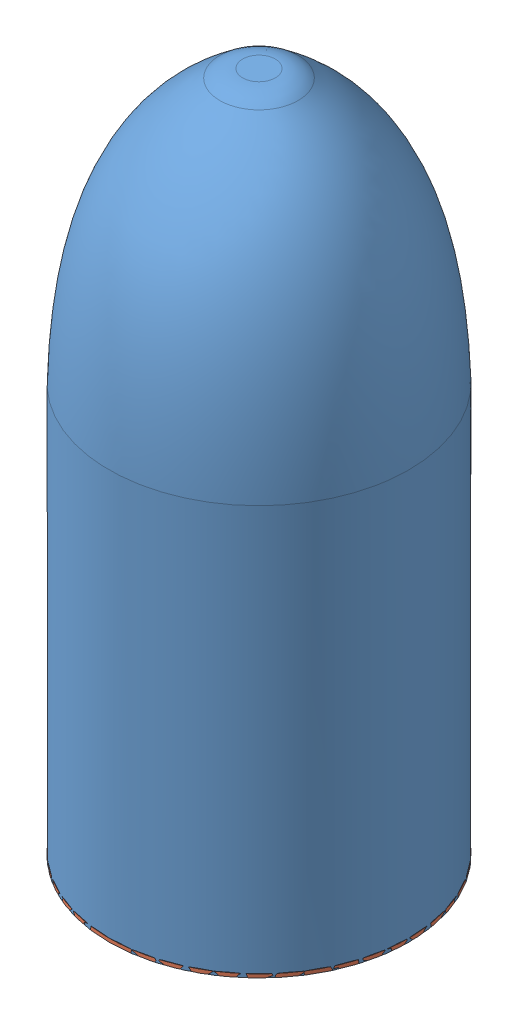
SolidWorks assembly payloadFairing_Combined, configuration Default. Lengths in mm.
Overall size (10071.32 19100 9565.41).
31 component instances, 20 part files, 2 mates.
Components (placement in the parent):
- topFairing-1: topFairing [Default] at (2105.8237 2257.1378 14978.6684) size (8561.42 19100 8561.42)
- Aeroshell-1: Aeroshell [Default] at (1984.2323 4396.0448 15237.9415) x (0.905382 0 0.424597) z (-0.424597 0 0.905382) size (5000 2906.08 5006.18)
  - Aeroshell-1: Aeroshell [Default] at origin size (5000 2400 5000)
  - Shell_platform-1: Shell_platform [Default] at (0 -6.0807 -290.3722) size (4880 5 4880)
  - Heatshield-2: Heatshield [Default] at (0 -6.0807 -289.9832) size (5000 500 5000)
  - TLS-1: TLS [Default] at (546.1998 194.1104 853.5417) size (100 100 207.41)
  - MARCI-1: MARCI [Default] at (875.0511 241.327 764.8193) x (0 1 0) z (-1 0 0) size (91.44 139.7 71.12)
  - MASPEX-1: MASPEX [Default] at (-25.9646 214.3299 -1050.0975) size (1000 500 350)
  - SEIS-1: SEIS [Default] at (58.1823 208.1212 482.2351) size (300 300 300)
  - solarDisk-1: solarDisk [Default] at (0 1382.782 -286.3686) size (5000 800 5000)
  - payloadStructure-1: payloadStructure [Default] at (0 101.113 -286.3686) x (0.999976 0 -0.006933) z (0.006933 0 0.999976) size (3000 1300 3000)
  - Power-1: Power [Default] at (0 238.099 -286.3686) x (0.999963 0 0.008641) z (-0.008641 0 0.999963) size (560 1100 560)
  - payloadStructureCap-1: payloadStructureCap [Default] at (0 98.9896 -282.8274) size (2800 100 2800)
  - dinitrogenTeTank-1: dinitrogenTeTank [Default] at (-2224.8888 1981.9547 -664.1718) size (329.4 329.4 329.4)
  - propellantTank-3: propellantTank [Default] at (2219.8151 1978.1665 -603.0175) size (367.6 367.6 367.6)
  - Telecommunications-1: Telecommunications [Default] at (-640.1939 166.9903 -153.3388) x (0 0 -1) z (1 0 0) size (1137.5 500 500)
  - CDH-1: CDH [Default] at (887.8472 185.5639 129.3374) size (650 500 500)
  - balloonFolded-1: balloonFolded [Default] at (-127.5968 1370.3812 -303.7981) size (1200 500 1200)
  - dinitrogenTeTank-3: dinitrogenTeTank [Default] at (-363.0979 337.0944 558.1732) size (329.4 329.4 329.4)
  - Thrusters-1: Thrusters [Default] at (-2206.5916 1841.4913 -294.457) size (500 250 250)
  - Thrusters-2: Thrusters [Default] at (2198.3507 1841.7122 -280.5469) size (500 250 250)
  - Thrusters-3: Thrusters [Default] at (-1.0862 1879.8297 1944.9528) x (0 0 -1) z (1 0 0) size (500 250 250)
  - Thrusters-4: Thrusters [Default] at (-10.7941 1872.7542 -2542.5496) x (0 0 -1) z (1 0 0) size (500 250 250)
  - Thrusters-5: Thrusters [Default] at (1329.6571 299.1643 -279.3619) x (-1 0 0) z (0 0 -1) size (500 250 250)
  - Thrusters-6: Thrusters [Default] at (6.8843 214.3078 1029.9018) x (0 0 -1) z (1 0 0) size (500 250 250)
  - Thrusters-7: Thrusters [Default] at (-1264.6008 208.5301 -284.9717) x (-1 0 0) z (0 0 -1) size (500 250 250)
  - Thrusters-8: Thrusters [Default] at (-34.6002 225.9228 -1592.8532) x (0 0 -1) z (1 0 0) size (500 250 250)
  - dinitrogenTeTank-4: dinitrogenTeTank [Default] at (707.9891 357.7286 -1029.6487) size (329.4 329.4 329.4)
  - propellantTank-4: propellantTank [Default] at (924.2922 381.1647 -649.1975) size (367.6 367.6 367.6)
  - ACS-1: ACS [Default] at (-769.0924 293.9054 -997.9203) size (975 500 500)
- payloadFairing-1: payloadFairing [Default] at (2105.8237 2257.1378 14978.6684) size (10071.32 1600 9565.41)
Mates (geometry in assembly coordinates):
- Concentric1: concentric aligned: circle of topFairing-1; circle of Aeroshell-1/Aeroshell-1
- Coincident2: coincident aligned: circle of topFairing-1; circle of payloadFairing-1
